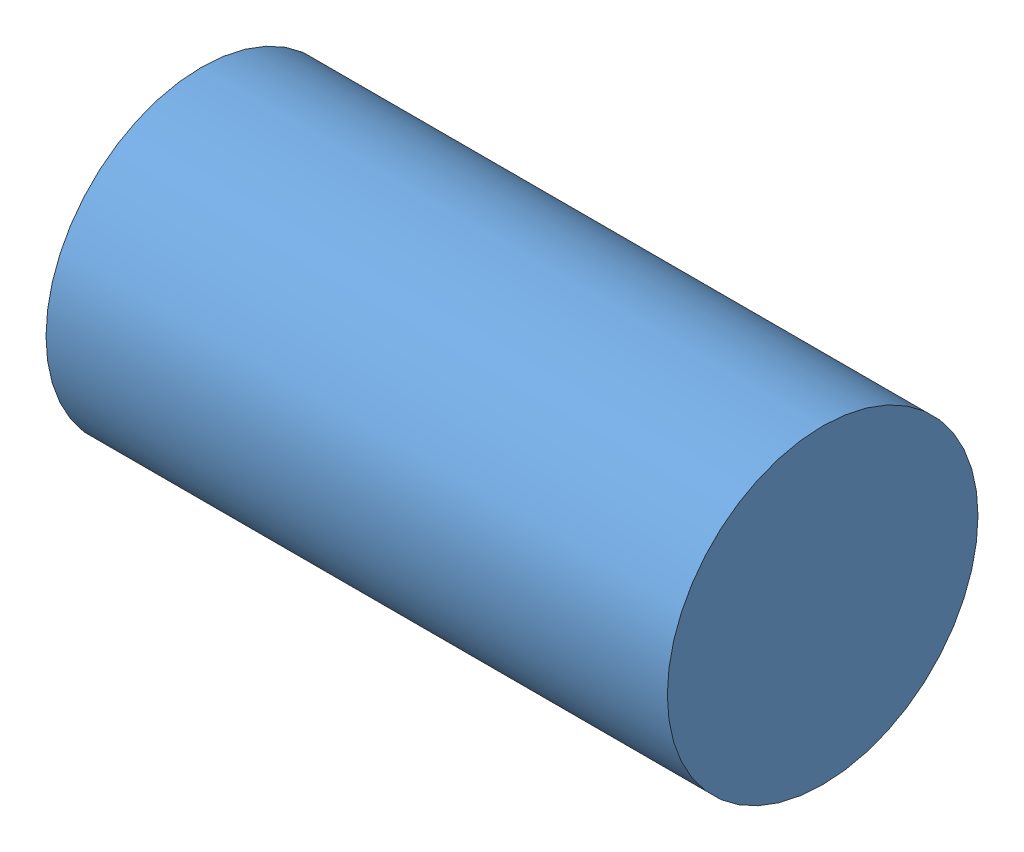
SolidWorks assembly vérin, configuration tige rentrée. Lengths in mm.
Overall size (105 50 50).
2 component instances, 2 part files, 5 mates.
Components (placement in the parent):
- fut-1: fut [Défaut] at origin size (100 50 50)
- piston-1: piston [Défaut] at (-5 0 0) x (1 0 0) z (0 0 -1) size (100 39 39)
Mates (geometry in assembly coordinates):
- Coïncidente1: coordinate: point of fut-1
- Coaxiale1: concentric aligned: cylinder of fut-1 through (-91.0032 0 0) axis (-1 0 0) radius 25; cylinder of piston-1 through (-32.4743 0 0) axis (-1 0 0) radius 5
- Coïncidente2: coincident anti-aligned: plane of fut-1 through (95 20 0) normal (-1 0 0); plane of piston-1 through (95 -19.5 0) normal (1 0 0)
- Coïncidente3: coincident anti-aligned: plane of fut-1 through (5 5.5 0) normal (1 0 0); plane of piston-1 through (5 -1.0466 4.8892) normal (-1 0 0)
- Coïncidente4: coincident anti-aligned: plane of piston-1 through (-5 0 0) normal (0 0 -1)
